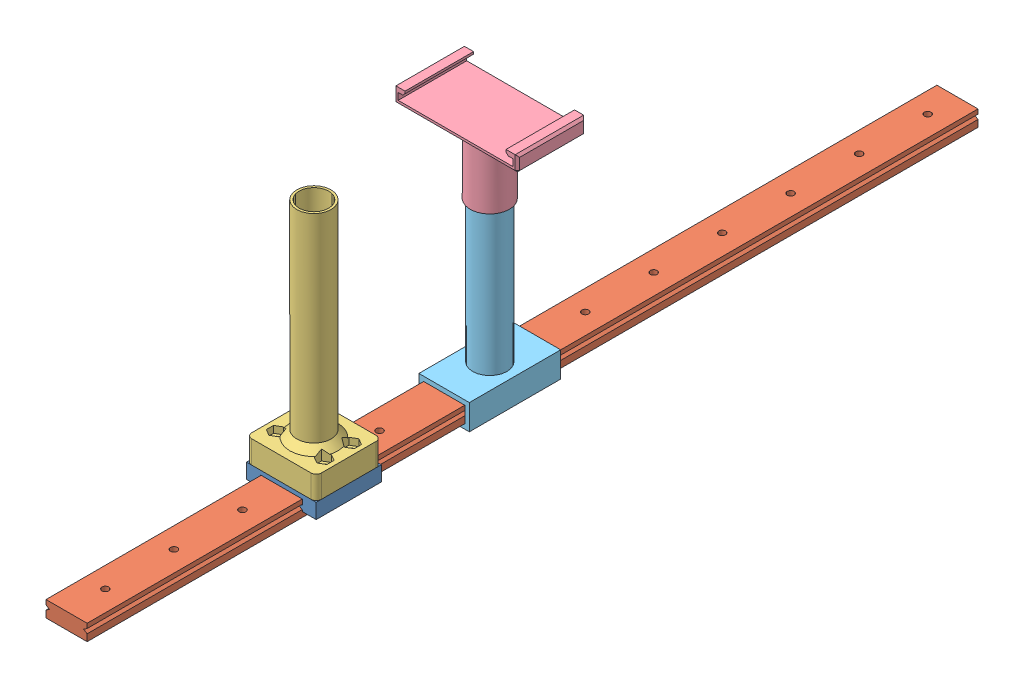
SolidWorks assembly thanh-gay-con-truot, configuration Default. Lengths in mm.
Overall size (54.2 111.05 390).
5 component instances, 5 part files, 10 mates.
Components (placement in the parent):
- Part1-1: Part1 [Default] at (-111.9944 30.0402 188.3227) size (30.5 6.56 28.5)
- thanh trượt-1: thanh trượt [Default] at (-111.9944 30.0402 -107.6479) size (18 7 390)
- Part2-1: Part2 [Default] at (-111.9944 35.4931 188.3227) x (1 0 0) z (0 1 0) size (30.5 28.5 100)
- Ban_nuoc-1: Ban_nuoc [Default] at (-112.0444 97.5402 97.0254) size (54.2 37 30)
- do-ban-nuoc-1: do-ban-nuoc [Default] at (-112.0444 29.9902 77.0254) size (22.1 101.1 40)
Mates (geometry in assembly coordinates):
- Distance3: distance = 0.15 mm anti-aligned: plane of Part1-1 through (-121.1444 33.6902 159.8227) normal (0 -1 0); plane of thanh trượt-1 through (-120.9944 33.5402 282.3521) normal (0 1 0)
- Distance4: distance = 0.15 mm anti-aligned: plane of Part1-1 through (-102.8444 31.46 159.8227) normal (-0.5547 0.83205 0); plane of thanh trượt-1 through (-109.9175 26.9249 282.3521) normal (0.5547 -0.83205 0)
- InPlace1: in place: plane of ? through (-127.2444 35.4931 39.0134) normal (0 1 0); plane of ? through (0 35.4931 0) normal (0 1 0); moOrthogonalPlaneRef_w of ? through (-127.2444 35.4931 39.0134) normal (0 1 0); plane of ? through (0 35.4931 0) normal (0 0 -1); plane of ? through (-127.2444 35.4931 39.0134) normal (0 1 0); plane of ? through (0 35.4931 0) normal (1 0 0); plane of Part1-1 through (-127.2444 35.4931 159.8227) normal (0 1 0); unknown of Part2-1
- Coincident5: coincident aligned: plane of Part1-1; plane of Part2-1
- Coincident6: coincident aligned: moOrthogonalPlaneRef_w of Part1-1 through (-111.9944 35.4931 188.3227) normal (0 0 -1); plane of Part2-1 through (-111.9944 35.4931 188.3227) normal (0 0 -1)
- Coincident7: coincident anti-aligned: moOrthogonalPlaneRef_w of Part1-1 through (-111.9944 35.4931 188.3227) normal (-1 0 0); plane of Part2-1 through (-111.9944 35.4931 188.3227) normal (1 0 0)
- Coincident2: coincident anti-aligned: plane of thanh trượt-1 through (-120.9944 33.5402 282.3521) normal (0 1 0); plane of do-ban-nuoc-1 through (-121.0944 33.5402 117.0254) normal (0 -1 0)
- Coincident3: coincident anti-aligned: plane of thanh trượt-1 through (-102.9944 26.5402 282.3521) normal (1 0 0); plane of do-ban-nuoc-1 through (-102.9944 26.4402 117.0254) normal (-1 0 0)
- Coincident4: coincident anti-aligned: plane of Ban_nuoc-1 through (-112.0444 125.5402 97.0254) normal (0 -1 0); plane of do-ban-nuoc-1 through (-112.0444 125.5402 97.0254) normal (0 1 0)
- Concentric2: concentric aligned: cylinder of Ban_nuoc-1 through (-112.0444 127.5402 97.0254) axis (0 -1 0) radius 7.55; cylinder of do-ban-nuoc-1 through (-112.0444 125.5402 97.0254) axis (0 -1 0) radius 7.5
